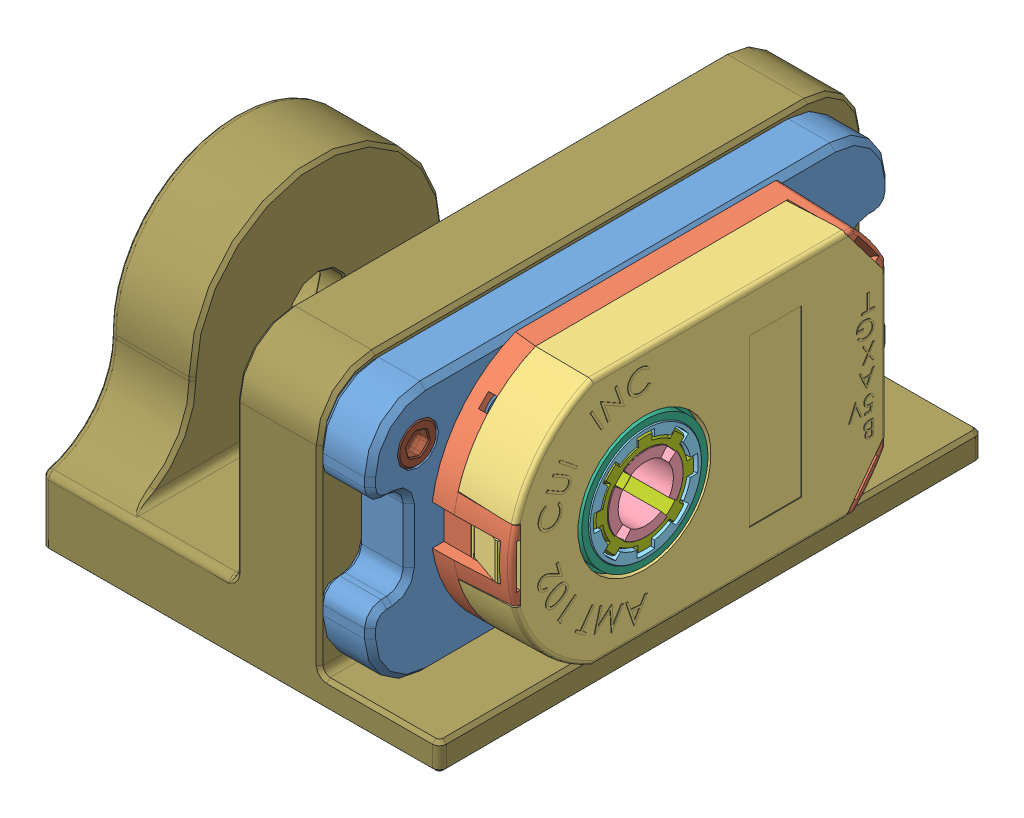
SolidWorks assembly 54+SlabAssembly, configuration Default. Lengths in mm.
Overall size (48.73 36.33 63.38).
15 component instances, 12 part files, 3 mates.
Components (placement in the parent):
- Slab_Assembly-1: Slab_Assembly [Default] at (-160.1338 -60.4895 59.2858) x (-0.003552 0 -0.999994) z (0.999994 0 -0.003552) size (59.83 36.33 21.74)
  - AARL_Puppy_18_01_01_055-1: AARL_Puppy_18_01_01_055 [Default] at (-49.6698 17.0323 53.8961) x (0 1 0) z (0 0 1) size (28.78 59.83 10.72)
  - CUI_DEVICES_cui_devices_amt102-0048-i6350-s-1: CUI_DEVICES_cui_devices_amt102-0048-i6350-s [Default] at (-49.6698 17.0323 63.6859) x (0 1 0) z (0 0 1) size (36.33 46.23 9.15)
    - CUI_DEVICES_amt-102-base-rev-k-1: CUI_DEVICES_amt-102-base-rev-k [Default] x (-1 0 0) z (0 0 -1) size (28.83 43.41 9.03)
    - CUI_DEVICES_amt-102-top-cover-rev-h-1: CUI_DEVICES_amt-102-top-cover-rev-h [Default] at (0 0 5.23) x (-1 0 0) z (0 0 -1) size (28.6 43.26 6.55)
    - CUI_DEVICES_amt-sleeve-rev-d(d)-1: CUI_DEVICES_amt-sleeve-rev-d(d) [Default] at (0 0 -2.42) x (0.999996 0.002864 0) z (0 0 1) size (10.79 10.79 7.8)
    - CUI_DEVICES_amt-hub-top-rev-d1-1: CUI_DEVICES_amt-hub-top-rev-d1 [Default] at (0 0 2.13) x (0.999996 0.002864 0) z (0 0 1) size (14 14 5.67)
    - CUI_DEVICES_amt-hub-bottom-rev-b-1: CUI_DEVICES_amt-hub-bottom-rev-b [Default] at (0 0 2.43) x (0.999998 -0.001942 0) z (0 0 1) size (17.3 17.3 3.2)
    - CUI_DEVICES_amt10x-shaft-adaptor-rev-e-1: CUI_DEVICES_amt10x-shaft-adaptor-rev-e [Default] at (0 0 0.03) x (0.999996 0.002864 0) z (0 0 1) size (11.8 11.8 7.8)
    - CUI_DEVICES_receiver-board-1: CUI_DEVICES_receiver-board [Default] at (72.2834 -20.351 3.03) x (-1 0 0) z (0 0 -1) size (26.5 26.62 0.41)
    - CUI_DEVICES_rotor-board-rev f-1: CUI_DEVICES_rotor-board-rev f [Default] at (0 0 2.13) x (0.807874 -0.589355 0) z (0 0 1) size (26 26 0.3)
    - CUI_DEVICES_transmitter-board amt10(amt-102)-1: CUI_DEVICES_transmitter-board amt10(amt-102) [Default] at (19.1596 -17.1102 1.22) x (-1 0 0) z (0 0 -1) size (26.63 38.43 4.41)
  - AARL_Puppy_18_04_01_017-2: AARL_Puppy_18_04_01_017 [Default] at (-66.6525 25.9223 59.9159) x (0.971112 0.238624 0) z (-0.238624 0.971112 0) size (4.65 12.57 4.65)
  - AARL_Puppy_18_04_01_017-3: AARL_Puppy_18_04_01_017 [Default] at (-17.8182 8.1423 59.8989) x (0.719542 0.694449 0) z (-0.694449 0.719542 0) size (4.65 12.57 4.65)
- AARL_Puppy_18_01_01_056_R-1: AARL_Puppy_18_01_01_056_R [Default] at (-137.7325 -61.1102 131.0888) x (0.003552 0 0.999994) z (-0.999994 0 0.003552) size (63.21 32.13 47.01)
Mates (geometry in assembly coordinates):
- Concentric2: concentric aligned: cylinder of Slab_Assembly-1/AARL_Puppy_18_01_01_055-1 through (-109.2791 -43.4572 96.8245) axis (0.999994 0 -0.003552) radius 3.9688; cylinder of AARL_Puppy_18_01_01_056_R-1 through (-109.4061 -43.4572 96.825) axis (0.999994 0 -0.003552) radius 4.0323
- Parallel3: parallel aligned: plane of Slab_Assembly-1/AARL_Puppy_18_01_01_055-1 through (-100.1746 -29.0681 71.392) normal (0 1 0); plane of AARL_Puppy_18_01_01_056_R-1 through (-106.2045 -28.9792 68.5559) normal (0 1 0)
- Coincident10: coincident anti-aligned: plane of Slab_Assembly-1/AARL_Puppy_18_01_01_055-1 through (-106.0616 -43.4572 108.7638) normal (-0.999994 0 0.003552); plane of AARL_Puppy_18_01_01_056_R-1 through (-106.2045 -57.9352 68.5559) normal (0.999994 0 -0.003552)
